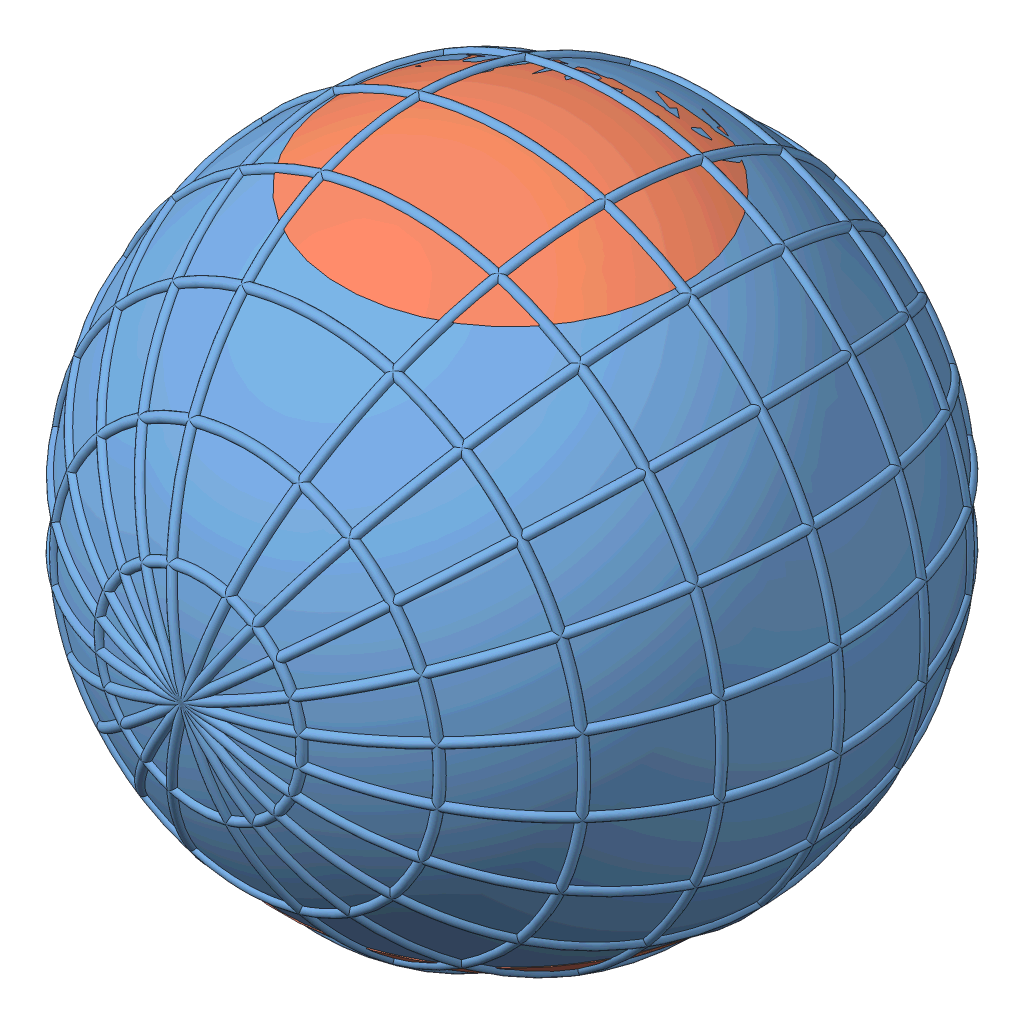
SolidWorks assembly Assem1, configuration Default. Lengths in mm.
Overall size (177.2 241.83 226.18).
2 component instances, 2 part files, 0 mates.
Components (placement in the parent):
- Wireframe-1: Wireframe [Default] at (-113.0775 63.5247 242.9024) x (0 1 0) z (0 0 1) size (241.83 177.2 226.18)
- Axle with two plates-1: Axle with two plates [Default] at (-112.8792 63.7573 243.426) x (0 1 0) z (0 0 1) size (140 97.98 97.98)
